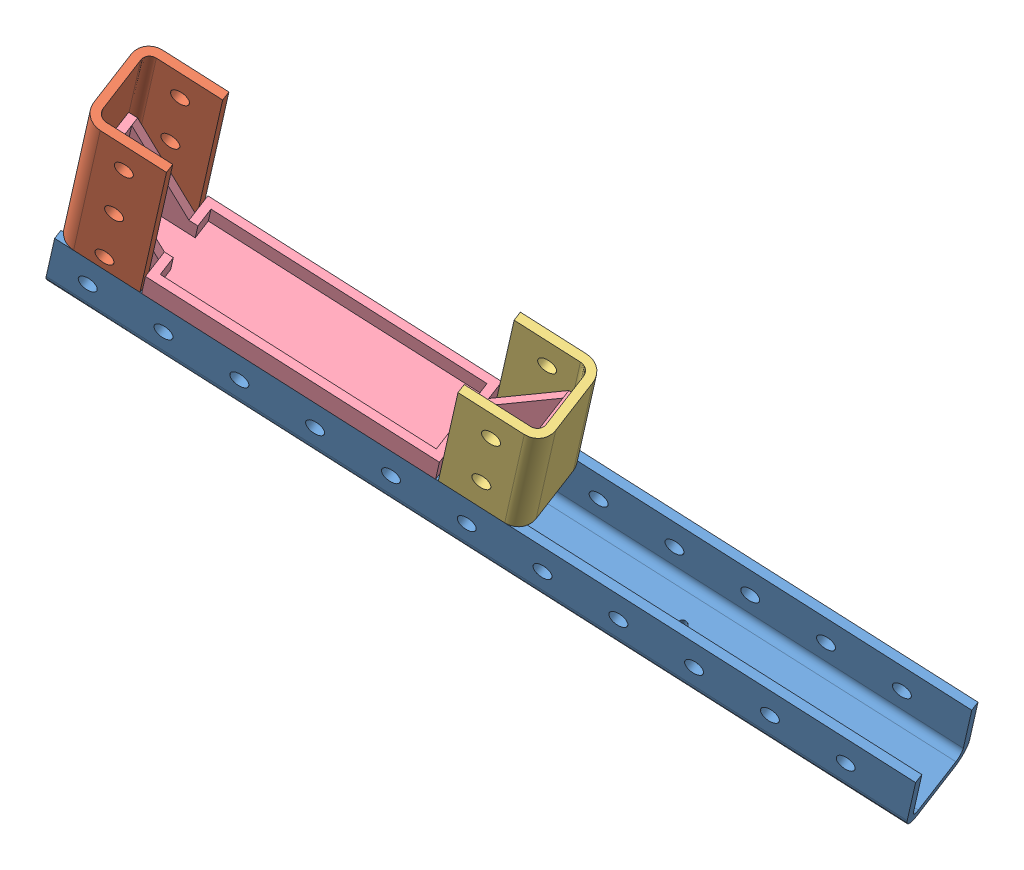
SolidWorks assembly F-Hand Complete, configuration Default. Lengths in mm.
Overall size (552.85 473.7 180).
4 component instances, 4 part files, 7 mates.
Components (placement in the parent):
- C-base 34cm-1: C-base 34cm [Default] at (956.6526 -166.43 -81.5617) x (-0.908944 0.321368 0.265601) z (-0.38426 -0.892915 -0.234623) size (444.34 31.75 28.57)
- C-channel6cm-1: C-channel6cm [Default] at (-132.7439 -581.215 -32.979) x (0.38426 0.892915 0.234623) z (-0.908944 0.321368 0.265601) size (444.34 31.75 28.57)
- C-Channel 4cm-1: C-Channel 4cm [Default] at (-5.5514 -640.6374 -93.5688) x (0.38426 0.892915 0.234623) z (0.908944 -0.321368 -0.265601) size (444.34 31.75 28.57)
- Holder-1: Holder [Default] at (208.6091 126.4129 137.339) x (-0.161759 0.315319 -0.935098) z (0.38426 0.892915 0.234623) size (31.8 150.5 40)
Mates (geometry in assembly coordinates):
- Coincident8: coincident aligned: line of C-base 34cm-1 through (436.3183 41.8123 86.3709) axis (-0.908944 0.321368 0.265601); line of C-channel6cm-1 through (200.0611 125.3438 155.4073) axis (-0.908944 0.321368 0.265601)
- Coincident9: coincident aligned: line of C-base 34cm-1 through (168.9522 144.5383 133.3075) axis (0.908944 -0.321368 -0.265601); line of C-channel6cm-1 through (174.724 142.4976 131.6209) axis (0.908944 -0.321368 -0.265601)
- Coincident11: coincident aligned: line of C-base 34cm-1 through (174.0881 134.5269 162.9969) axis (-0.161759 0.315319 -0.935098); line of C-channel6cm-1 through (173.0609 136.5292 157.059) axis (-0.161759 0.315319 -0.935098)
- Coincident13: coincident aligned: line of C-base 34cm-1 through (436.3183 41.8123 86.3709) axis (-0.908944 0.321368 0.265601); line of C-Channel 4cm-1 through (311.1568 86.0646 122.9442) axis (-0.908944 0.321368 0.265601)
- Coincident14: coincident aligned: line of C-base 34cm-1 through (168.9522 144.5383 133.3075) axis (0.908944 -0.321368 -0.265601); line of C-Channel 4cm-1 through (285.8197 103.2184 99.1578) axis (0.908944 -0.321368 -0.265601)
- Distance3: distance = 100 mm anti-aligned: plane of C-Channel 4cm-1 through (305.6474 149.2928 111.2644) normal (-0.908944 0.321368 0.265601); plane of C-channel6cm-1 through (226.9593 187.8478 171.831) normal (0.908944 -0.321368 -0.265601)
- Coincident30: coincident anti-aligned: line of C-base 34cm-1 through (168.9522 144.5383 133.3075) axis (0.908944 -0.321368 -0.265601); line of Holder-1 through (285.0016 103.5076 99.3969) axis (-0.908944 0.321368 0.265601)
